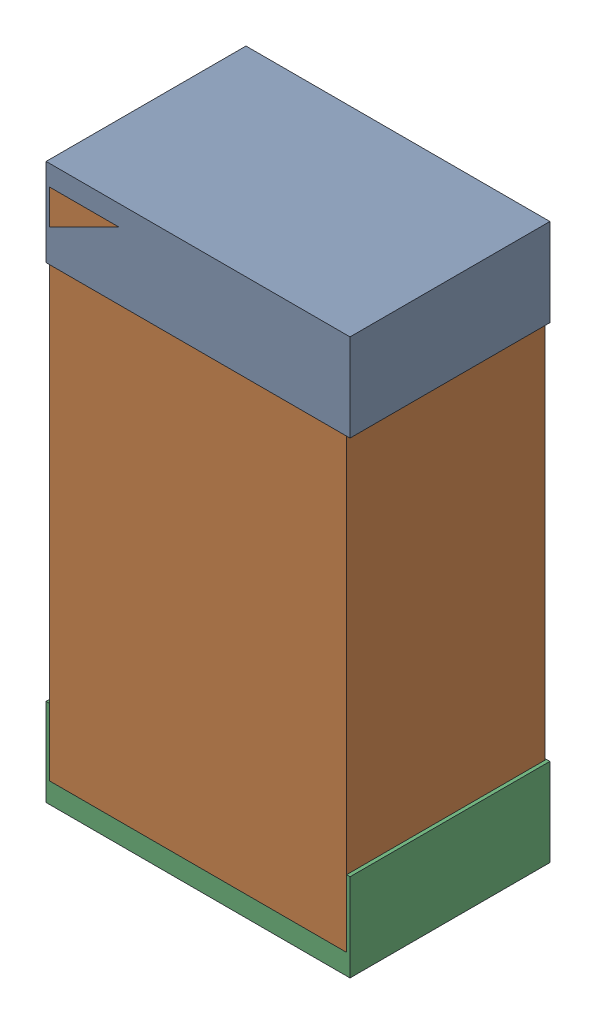
SolidWorks assembly R44Kanaloa_v2.0.0_Motor, configuration Default. Lengths in mm.
Overall size (1.3 2.38 0.85).
6 component instances, 2 part files, 0 mates.
Components (placement in the parent):
- 330415056-1: 330415056 [Default] at (124.46 125.968 -1.9574) size (1.3 0.38 0.85)
  - Extruded_2-1: Extruded_2 [Default] at origin size (1.3 0.38 0.85)
- 334787376-1: 334787376 [Default] at (124.46 124.968 -1.9524) size (1.27 2.2 0.85)
  - Extruded_16-1: Extruded_16 [Default] at origin size (1.27 2.2 0.85)
- 330415056-2: 330415056 [Default] at (124.46 123.968 -1.9574) size (1.3 0.38 0.85)
  - Extruded_2-1: Extruded_2 [Default] at origin size (1.3 0.38 0.85)
